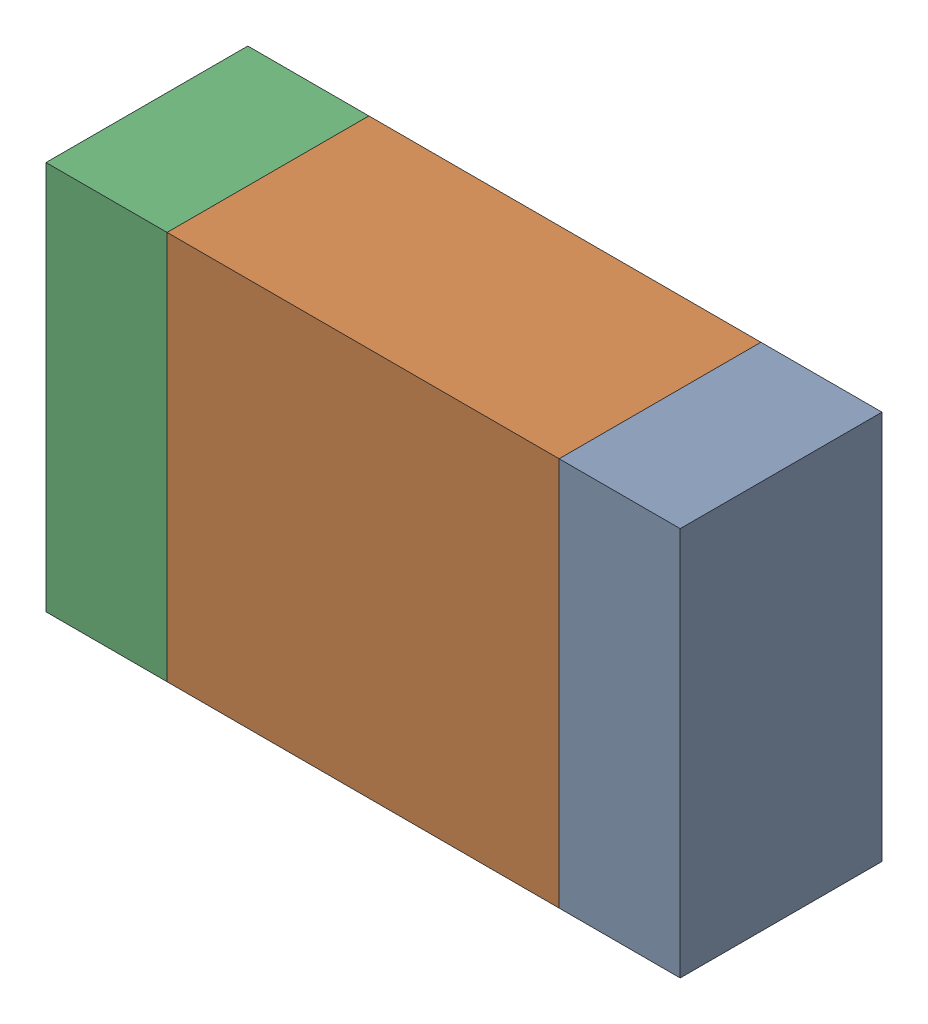
SolidWorks assembly R7-1, configuration Default. Lengths in mm.
Overall size (2.2 1.35 0.7).
6 component instances, 2 part files, 0 mates.
Components (placement in the parent):
- 959209344-1-1: 959209344-1 [Default] at (76.5821 79.5961 0) size (0.42 1.35 0.7)
  - Extruded-56-1: Extruded-56 [Default] at origin size (0.42 1.35 0.7)
- 959209480-1-1: 959209480-1 [Default] at (75.6921 79.5961 0) size (1.36 1.35 0.7)
  - Extruded-57-1: Extruded-57 [Default] at origin size (1.36 1.35 0.7)
- 959209344-1-2: 959209344-1 [Default] at (74.8021 79.5961 0) size (0.42 1.35 0.7)
  - Extruded-56-1: Extruded-56 [Default] at origin size (0.42 1.35 0.7)
